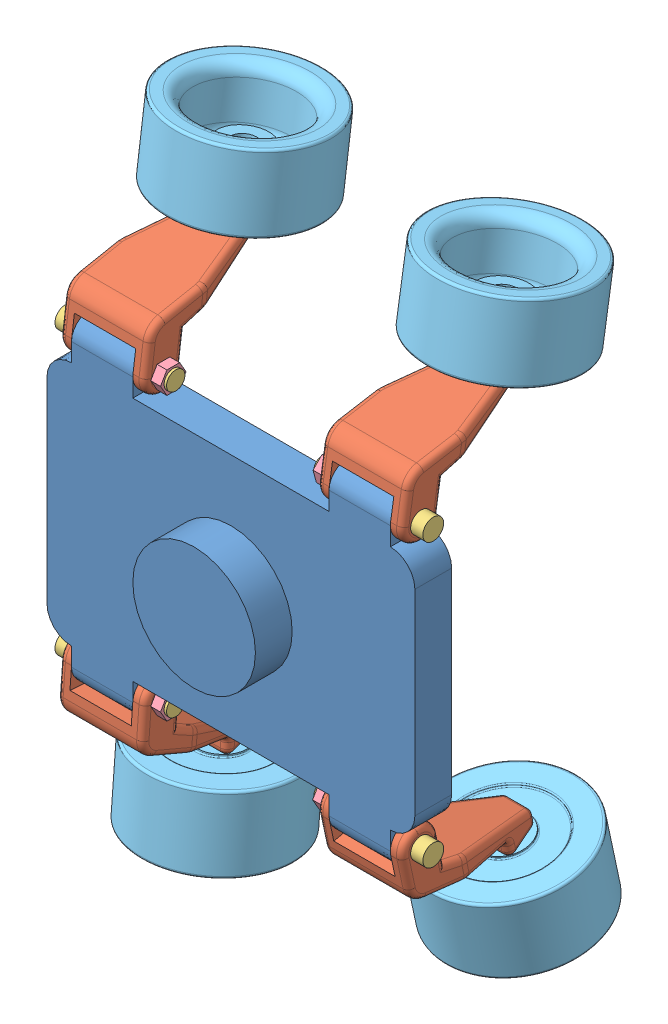
SolidWorks assembly montaj, configuration Varsayılan. Lengths in mm.
Overall size (3564.46 5141.4 2326.04).
17 component instances, 5 part files, 32 mates.
Components (placement in the parent):
- sasi-1: sasi [Varsayılan] at (160.6056 -0.2081 3000) size (3000 2600 600)
- dingil-1: dingil [Varsayılan] at (-860.683 999.5199 3001.4618) x (1 0 0) z (0 0.132276 0.991213) size (700 1127.49 1176.87)
- dingil-2: dingil [Varsayılan] at (1239.317 995.9274 3002.0122) x (1 0 0) z (0 0.156251 0.987717) size (700 1127.49 1176.87)
- dingil-3: dingil [Varsayılan] at (-1227.8005 -1290.0695 3000.3646) x (-1 0 0) z (0 0.077279 0.997009) size (700 1127.49 1176.87)
- dingil-4: dingil [Varsayılan] at (872.1995 -1247.0245 3003.5673) x (-1 0 0) z (0 -0.209827 0.977738) size (700 1127.49 1176.87)
- dingil_mili-1: dingil_mili [Varsayılan] at (605.7583 1020.4387 3150) x (0 -0.996183 0.087291) z (1 0 0) size (170 170 900)
- dingil_mili_somunu-1: dingil_mili_somunu [Varsayılan] at (705.7583 1020.4387 3150) x (0 0.257019 0.966406) z (-1 0 0) size (207.85 180 80)
- tekerlek-1: tekerlek [Varsayılan] at (-1044.2417 -2720.6916 2382.2012) x (-0.994435 0.008141 0.105032) z (0 0.997009 -0.077279) size (1200 1200 600)
- tekerlek-2: tekerlek [Varsayılan] at (1055.7583 -2442.3903 2003.6142) x (0.9937 0.023515 -0.109574) z (0 0.977738 0.209827) size (1200 1200 600)
- tekerlek-3: tekerlek [Varsayılan] at (1055.7583 2243.9927 2068.6642) x (0.895089 -0.06967 -0.440411) z (0 -0.987717 0.156251) size (1200 1200 600)
- tekerlek-4: tekerlek [Varsayılan] at (-1044.2417 2269.8308 2098.6242) x (-0.999993 0.000495 0.003706) z (0 -0.991213 0.132276) size (1200 1200 600)
- dingil_mili-2: dingil_mili [Varsayılan] at (-594.2417 -1279.5613 3150) x (0 0.23421 -0.972186) z (-1 0 0) size (170 170 900)
- dingil_mili_somunu-2: dingil_mili_somunu [Varsayılan] at (-614.2417 1020.4387 3150) x (0 0 1) z (-1 0 0) size (207.85 180 80)
- dingil_mili-3: dingil_mili [Varsayılan] at (605.7583 -1279.5613 3150) x (0 0.609422 0.792846) z (1 0 0) size (170 170 900)
- dingil_mili-4: dingil_mili [Varsayılan] at (-594.2417 1020.4387 3150) x (0 -0.466856 0.884333) z (-1 0 0) size (170 170 900)
- dingil_mili_somunu-3: dingil_mili_somunu [Varsayılan] at (705.7583 -1279.5613 3150) x (0 0 1) z (-1 0 0) size (207.85 180 80)
- dingil_mili_somunu-4: dingil_mili_somunu [Varsayılan] at (-694.2417 -1279.5613 3150) x (0 0 -1) z (1 0 0) size (207.85 180 80)
Mates (geometry in assembly coordinates):
- Eş Merkezli1: concentric anti-aligned: cylinder of sasi-1 through (-2180.2417 1020.4387 3150) axis (1 0 0) radius 75; cylinder of dingil-1 through (-633.2417 1020.4387 3150) axis (-1 0 0) radius 75
- Çakışık1: coincident anti-aligned: circle of sasi-1; circle of dingil-1
- Eş Merkezli2: concentric anti-aligned: cylinder of sasi-1 through (-2180.2417 1020.4387 3150) axis (1 0 0) radius 75; cylinder of dingil-2 through (1466.7583 1020.4387 3150) axis (-1 0 0) radius 75
- Çakışık2: coincident anti-aligned: circle of sasi-1; circle of dingil-2
- Eş Merkezli3: concentric aligned: cylinder of sasi-1 through (-2180.2417 -1279.5613 3150) axis (1 0 0) radius 75; cylinder of dingil-3 through (-1455.2417 -1279.5613 3150) axis (1 0 0) radius 75
- Çakışık3: coincident anti-aligned: circle of sasi-1; circle of dingil-3
- Eş Merkezli4: concentric aligned: cylinder of sasi-1 through (-2180.2417 -1279.5613 3150) axis (1 0 0) radius 75; cylinder of dingil-4 through (644.7583 -1279.5613 3150) axis (1 0 0) radius 75
- Çakışık4: coincident anti-aligned: circle of sasi-1; circle of dingil-4
- Eş Merkezli5: concentric aligned: cylinder of dingil-2 through (1466.7583 1020.4387 3150) axis (-1 0 0) radius 75; cylinder of dingil_mili-1 through (1405.7583 1020.4387 3150) axis (-1 0 0) radius 75
- Çakışık5: coincident anti-aligned: plane of dingil-2 through (1405.7583 1290.8057 3259.0948) normal (1 0 0); plane of dingil_mili-1 through (1405.7583 1020.4387 3150) normal (-1 0 0)
- Eş Merkezli6: concentric anti-aligned: cylinder of dingil_mili-1 through (1405.7583 1020.4387 3150) axis (-1 0 0) radius 75; cylinder of dingil_mili_somunu-1 through (571.7583 1020.4387 3150) axis (1 0 0) radius 75
- Çakışık6: coincident anti-aligned: plane of dingil-2 through (705.7583 1290.8057 3259.0948) normal (-1 0 0); plane of dingil_mili_somunu-1 through (705.7583 1020.4387 3150) normal (1 0 0)
- Eş Merkezli7: concentric aligned: cylinder of dingil-3 through (-1044.2417 -2321.8878 2351.2894) axis (0 0.997009 -0.077279) radius 100; cylinder of tekerlek-1 through (-1044.2417 -2720.6916 2382.2012) axis (0 0.997009 -0.077279) radius 100
- Çakışık7: coincident anti-aligned: circle of dingil-3; circle of tekerlek-1
- Eş Merkezli8: concentric aligned: cylinder of dingil-4 through (1055.7583 -2051.2949 2087.5451) axis (0 0.977738 0.209827) radius 100; cylinder of tekerlek-2 through (1055.7583 -2442.3903 2003.6142) axis (0 0.977738 0.209827) radius 100
- Çakışık8: coincident anti-aligned: circle of dingil-4; circle of tekerlek-2
- Eş Merkezli9: concentric aligned: cylinder of dingil-2 through (1055.7583 1848.9057 2131.1646) axis (0 -0.987717 0.156251) radius 100; cylinder of tekerlek-3 through (1055.7583 2243.9927 2068.6642) axis (0 -0.987717 0.156251) radius 100
- Çakışık9: coincident anti-aligned: circle of dingil-2; circle of tekerlek-3
- Eş Merkezli10: concentric aligned: cylinder of dingil-1 through (-1044.2417 1873.3456 2151.5347) axis (0 -0.991213 0.132276) radius 100; cylinder of tekerlek-4 through (-1044.2417 2269.8308 2098.6242) axis (0 -0.991213 0.132276) radius 100
- Çakışık10: coincident anti-aligned: circle of dingil-1; circle of tekerlek-4
- Eş Merkezli11: concentric aligned: cylinder of dingil-3 through (-1455.2417 -1279.5613 3150) axis (1 0 0) radius 75; cylinder of dingil_mili-2 through (-1394.2417 -1279.5613 3150) axis (1 0 0) radius 75
- Çakışık11: coincident anti-aligned: plane of dingil-3 through (-1394.2417 -1517.2218 3318.8713) normal (-1 0 0); plane of dingil_mili-2 through (-1394.2417 -1279.5613 3150) normal (1 0 0)
- Eş Merkezli12: concentric anti-aligned: cylinder of dingil-4 through (644.7583 -1279.5613 3150) axis (1 0 0) radius 75; cylinder of dingil_mili-3 through (1405.7583 -1279.5613 3150) axis (-1 0 0) radius 75
- Çakışık12: coincident anti-aligned: plane of dingil-4 through (1405.7583 -1555.47 3244.204) normal (1 0 0); plane of dingil_mili-3 through (1405.7583 -1279.5613 3150) normal (-1 0 0)
- Eş Merkezli13: concentric anti-aligned: cylinder of dingil-1 through (-633.2417 1020.4387 3150) axis (-1 0 0) radius 75; cylinder of dingil_mili-4 through (-1394.2417 1020.4387 3150) axis (1 0 0) radius 75
- Çakışık13: coincident anti-aligned: plane of dingil-1 through (-1394.2417 1288.0833 3265.6129) normal (-1 0 0); plane of dingil_mili-4 through (-1394.2417 1020.4387 3150) normal (1 0 0)
- Eş Merkezli14: concentric anti-aligned: circle of dingil_mili_somunu-2; cylinder of dingil_mili-4 through (-1494.2417 1020.4387 3150) axis (1 0 0) radius 85
- Çakışık14: coincident anti-aligned: plane of dingil-1 through (-694.2417 1288.0833 3265.6129) normal (1 0 0); plane of dingil_mili_somunu-2 through (-694.2417 1020.4387 3150) normal (-1 0 0)
- Eş Merkezli15: concentric anti-aligned: cylinder of dingil_mili-2 through (-1494.2417 -1279.5613 3150) axis (1 0 0) radius 85; cylinder of dingil_mili_somunu-4 through (-560.2417 -1279.5613 3150) axis (-1 0 0) radius 75
- Çakışık15: coincident anti-aligned: plane of dingil-3 through (-694.2417 -1517.2218 3318.8713) normal (1 0 0); plane of dingil_mili_somunu-4 through (-694.2417 -1279.5613 3150) normal (-1 0 0)
- Eş Merkezli16: concentric anti-aligned: cylinder of dingil_mili-3 through (1405.7583 -1279.5613 3150) axis (-1 0 0) radius 75; cylinder of dingil_mili_somunu-3 through (571.7583 -1279.5613 3150) axis (1 0 0) radius 75
- Çakışık16: coincident anti-aligned: plane of dingil-4 through (705.7583 -1555.47 3244.204) normal (-1 0 0); plane of dingil_mili_somunu-3 through (705.7583 -1279.5613 3150) normal (1 0 0)
